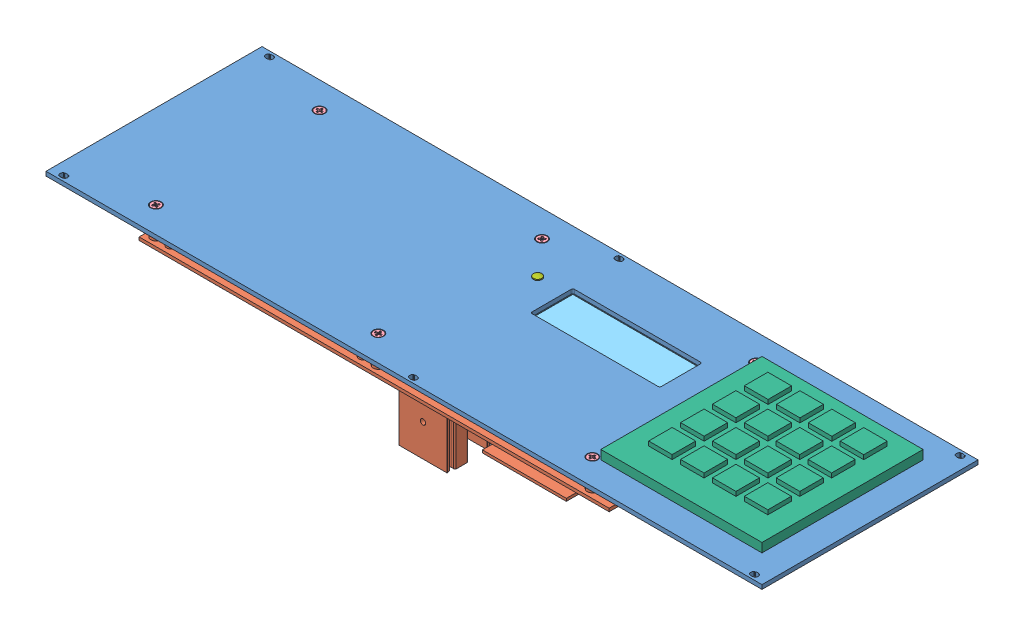
SolidWorks assembly MLA-0387-M0, configuration Default. Lengths in mm.
Overall size (426.52 63.69 128.7).
20 component instances, 9 part files, 41 mates.
Components (placement in the parent):
- MLA-0387-M1-1: MLA-0387-M1 [Default] at (-7.6092 -164.7802 590.2232) size (426.52 2.5 128.7)
- MLA-0387-P0-PB1-2: MLA-0387-P0-PB1 [Default] at (40.1108 198.8099 361.2233) x (1 0 0) z (0 1 0) size (280 107.5 53.19)
- pan_head_phillip_M2x4-1: pan_head_phillip_M2x4 [Default] at (204.3608 203.4199 260.2232) x (1 0 0) z (0 0 1) size (4 9.78 4)
- pan_head_phillip_M2x4-2: pan_head_phillip_M2x4 [Default] at (297.3608 203.4199 260.2232) x (-1 0 0) z (0 0 -1) size (4 9.78 4)
- pan_head_phillip_M2x4-3: pan_head_phillip_M2x4 [Default] at (204.3609 203.4199 315.2232) x (1 0 0) z (0 0 1) size (4 9.78 4)
- pan_head_phillip_M2x4-4: pan_head_phillip_M2x4 [Default] at (297.3609 203.4199 315.2232) x (1 0 0) z (0 0 1) size (4 9.78 4)
- SCREW_ISO 7046-1: SCREW_ISO 7046 [VIJAK M 3x 10] at (45.1108 215.3198 258.7232) x (0 -1 0) z (0 0 1) size (10 5.6 5.6)
- SCREW_ISO 7046-2: SCREW_ISO 7046 [VIJAK M 3x 10] at (45.1108 215.3198 356.2232) x (0 -1 0) z (-0.86006 0 -0.510193) size (10 5.6 5.6)
- SCREW_ISO 7046-3: SCREW_ISO 7046 [VIJAK M 3x 10] at (177.6108 215.2333 356.2232) x (0 -1 0) z (0.989385 0 -0.145321) size (10 5.6 5.6)
- SCREW_ISO 7046-4: SCREW_ISO 7046 [VIJAK M 3x 10] at (177.6108 215.3198 258.7232) x (0 -1 0) z (0.648115 0 0.761542) size (10 5.6 5.6)
- SCREW_ISO 7046-5: SCREW_ISO 7046 [VIJAK M 3x 10] at (305.1108 215.3198 258.7232) x (0 -1 0) z (0 0 1) size (10 5.6 5.6)
- SCREW_ISO 7046-6: SCREW_ISO 7046 [VIJAK M 3x 10] at (305.1108 215.3198 356.2232) x (0 -1 0) z (0 0 1) size (10 5.6 5.6)
- NHD-0420D3Z-FL-GBW-V3-3: NHD-0420D3Z-FL-GBW-V3 [Default] at (201.8609 201.8199 317.7232) x (1 0 0) z (0 1 0) size (98 60 10.6)
- Storm_7016010-4: Storm_7016010 [Default] at (309.2008 215.3198 355.2732) x (1 0 0) z (0 1 0) size (96 96 22)
- PLW5-500-1: PLW5-500 [Default] at (196.1108 215.3198 279.8132) size (5.25 13.97 5.07)
- MLA-0387-M7-1: MLA-0387-M7 [Default] at (49.1107 206.8199 361.2233) x (1 0 0) z (0 0 1) size (124.5 3 107.5)
- M2_5x8_Pan_head-1: M2_5x8_Pan_head [Default] at (54.1107 209.8199 258.7233) x (0 -1 0) z (-0.996671 0 -0.081529) size (13.3 7.99 5.14)
- M2_5x8_Pan_head-2: M2_5x8_Pan_head [Default] at (54.1107 209.8199 356.2233) x (0 -1 0) z (0.171735 0 0.985143) size (13.3 7.99 5.14)
- M2_5x8_Pan_head-3: M2_5x8_Pan_head [Default] at (168.6107 209.8199 356.2233) x (0 -1 0) z (0.996977 0 0.077698) size (13.3 7.99 5.14)
- M2_5x8_Pan_head-4: M2_5x8_Pan_head [Default] at (168.6107 209.8199 258.7233) x (0 -1 0) z (-0.397383 0 0.917653) size (13.3 7.99 5.14)
Mates (geometry in assembly coordinates):
- Concentric32: concentric aligned: cone of MLA-0387-M1-1 through (45.1108 215.3198 258.7232) axis (0 -1 0); cone of SCREW_ISO 7046-1 through (45.1108 213.8198 258.7232) axis (0 -1 0)
- Coincident46: coincident aligned: plane of MLA-0387-M1-1 through (0.4712 215.3198 287.1473) normal (0 1 0); plane of SCREW_ISO 7046-1 through (45.1108 215.3198 258.7232) normal (0 1 0)
- Concentric33: concentric aligned: cone of MLA-0387-M1-1 through (45.1108 215.3198 356.2232) axis (0 -1 0); cone of SCREW_ISO 7046-2 through (45.1108 213.8198 356.2232) axis (0 -1 0)
- Coincident47: coincident aligned: plane of MLA-0387-M1-1 through (0.4712 215.3198 287.1473) normal (0 1 0); plane of SCREW_ISO 7046-2 through (45.1108 215.3198 356.2232) normal (0 1 0)
- Coincident48: coincident: circle of MLA-0387-M1-1; cone of SCREW_ISO 7046-3 through (177.6108 213.7333 356.2232) axis (0 -1 0)
- Concentric34: concentric aligned: cone of MLA-0387-M1-1 through (177.6108 215.3198 258.7232) axis (0 -1 0); cone of SCREW_ISO 7046-4 through (177.6108 213.8198 258.7232) axis (0 -1 0)
- Coincident49: coincident aligned: plane of MLA-0387-M1-1 through (0.4712 215.3198 287.1473) normal (0 1 0); plane of SCREW_ISO 7046-4 through (177.6108 215.3198 258.7232) normal (0 1 0)
- Concentric35: concentric aligned: cone of MLA-0387-M1-1 through (305.1108 215.3198 258.7232) axis (0 -1 0); cone of SCREW_ISO 7046-5 through (305.1108 213.8198 258.7232) axis (0 -1 0)
- Coincident50: coincident aligned: plane of MLA-0387-M1-1 through (0.4712 215.3198 287.1473) normal (0 1 0); plane of SCREW_ISO 7046-5 through (305.1108 215.3198 258.7232) normal (0 1 0)
- Concentric36: concentric aligned: cone of MLA-0387-M1-1 through (305.1108 215.3198 356.2232) axis (0 -1 0); cone of SCREW_ISO 7046-6 through (305.1108 213.8198 356.2232) axis (0 -1 0)
- Coincident51: coincident aligned: plane of MLA-0387-M1-1 through (0.4712 215.3198 287.1473) normal (0 1 0); plane of SCREW_ISO 7046-6 through (305.1108 215.3198 356.2232) normal (0 1 0)
- Coincident60: coincident aligned: plane of MLA-0387-M1-1 through (0.4712 212.8198 287.1473) normal (0 -1 0); circle of MLA-0387-P0-PB1-2
- Concentric37: concentric aligned: cylinder of MLA-0387-M1-1 through (177.6108 215.3198 258.7232) axis (0 -1 0) radius 1.75; cylinder of MLA-0387-P0-PB1-2 through (177.6108 206.4198 258.7232) axis (0 -1 0) radius 3
- Concentric38: concentric aligned: cylinder of MLA-0387-M1-1 through (305.1108 215.3198 356.2232) axis (0 -1 0) radius 1.75; cylinder of MLA-0387-P0-PB1-2 through (305.1108 206.4199 356.2232) axis (0 -1 0) radius 3
- Coincident54: coincident aligned: circle of MLA-0387-P0-PB1-2; plane of NHD-0420D3Z-FL-GBW-V3-3 through (201.8609 201.8199 317.7232) normal (0 -1 0)
- Concentric39: concentric aligned: cylinder of NHD-0420D3Z-FL-GBW-V3-3 through (204.3608 201.8199 260.2232) axis (0 1 0) radius 1.25; cylinder of MLA-0387-P0-PB1-2 through (204.3608 197.4199 260.2232) axis (0 1 0) radius 2.175
- Concentric40: concentric aligned: cylinder of MLA-0387-P0-PB1-2 through (297.3608 197.4199 260.2232) axis (0 1 0) radius 2.175; cylinder of NHD-0420D3Z-FL-GBW-V3-3 through (297.3608 201.8199 260.2232) axis (0 1 0) radius 1.25
- Concentric41: concentric anti-aligned: cylinder of pan_head_phillip_M2x4-1 through (204.3608 205.2049 260.2232) axis (0 -1 0) radius 2; cylinder of NHD-0420D3Z-FL-GBW-V3-3 through (204.3608 201.8199 260.2232) axis (0 1 0) radius 1.25
- Coincident55: coincident anti-aligned: plane of pan_head_phillip_M2x4-1 through (204.3608 203.4199 260.2232) normal (0 -1 0); plane of NHD-0420D3Z-FL-GBW-V3-3 through (201.8609 203.4199 317.7232) normal (0 1 0)
- Concentric42: concentric anti-aligned: cylinder of pan_head_phillip_M2x4-2 through (297.3608 205.2049 260.2232) axis (0 -1 0) radius 2; cylinder of NHD-0420D3Z-FL-GBW-V3-3 through (297.3608 201.8199 260.2232) axis (0 1 0) radius 1.25
- Coincident56: coincident anti-aligned: plane of pan_head_phillip_M2x4-2 through (297.3608 203.4199 260.2232) normal (0 -1 0); plane of NHD-0420D3Z-FL-GBW-V3-3 through (201.8609 203.4199 317.7232) normal (0 1 0)
- Concentric43: concentric anti-aligned: cylinder of pan_head_phillip_M2x4-4 through (297.3609 205.2049 315.2232) axis (0 -1 0) radius 2; cylinder of NHD-0420D3Z-FL-GBW-V3-3 through (297.3609 201.8199 315.2232) axis (0 1 0) radius 1.25
- Coincident57: coincident anti-aligned: plane of pan_head_phillip_M2x4-4 through (297.3609 203.4199 315.2232) normal (0 -1 0); plane of NHD-0420D3Z-FL-GBW-V3-3 through (201.8609 203.4199 317.7232) normal (0 1 0)
- Concentric44: concentric anti-aligned: cylinder of pan_head_phillip_M2x4-3 through (204.3609 205.2049 315.2232) axis (0 -1 0) radius 2; cylinder of NHD-0420D3Z-FL-GBW-V3-3 through (204.3609 201.8199 315.2232) axis (0 1 0) radius 1.25
- Coincident58: coincident anti-aligned: plane of pan_head_phillip_M2x4-3 through (204.3609 203.4199 315.2232) normal (0 -1 0); plane of NHD-0420D3Z-FL-GBW-V3-3 through (201.8609 203.4199 317.7232) normal (0 1 0)
- Concentric45: concentric anti-aligned: circle of MLA-0387-M1-1; cylinder of Storm_7016010-4 through (389.2008 201.3198 339.2732) axis (0 1 0) radius 1.5
- Concentric46: concentric anti-aligned: circle of MLA-0387-M1-1; cylinder of Storm_7016010-4 through (325.2008 201.3198 275.2732) axis (0 1 0) radius 1.5
- Coincident61: coincident anti-aligned: plane of MLA-0387-M1-1 through (0.4712 215.3198 287.1473) normal (0 1 0); plane of Storm_7016010-4 through (309.2008 215.3198 355.2732) normal (0 -1 0)
- Concentric47: concentric aligned: cylinder of MLA-0387-M1-1 through (196.1108 205.3198 279.8132) axis (0 1 0) radius 1.98; cylinder of PLW5-500-1 through (196.1108 203.8054 279.8132) axis (0 1 0) radius 1.9304
- Coincident62: coincident aligned: plane of MLA-0387-M1-1 through (0.4712 215.3198 287.1473) normal (0 1 0); circle of PLW5-500-1
- Concentric48: concentric: circle of MLA-0387-P0-PB1-2; cylinder of MLA-0387-M7-1 through (54.1107 206.8199 258.7233) axis (0 1 0) radius 1.5
- Concentric49: concentric: cylinder of MLA-0387-P0-PB1-2 through (168.6107 194.9717 356.2233) axis (0 -1 0) radius 1.0065; cylinder of MLA-0387-M7-1 through (168.6107 206.8199 356.2233) axis (0 1 0) radius 1.5
- Coincident63: coincident anti-aligned: plane of MLA-0387-P0-PB1-2 through (171.1607 206.8199 356.2233) normal (0 1 0); plane of MLA-0387-M7-1 through (49.1107 206.8199 361.2233) normal (0 -1 0)
- Concentric50: concentric: cylinder of MLA-0387-P0-PB1-2 through (54.1107 194.9716 258.7233) axis (0 -1 0) radius 1.0065; cylinder of M2_5x8_Pan_head-1 through (54.1107 204.379 258.7233) axis (0 1 0) radius 1
- Coincident64: coincident anti-aligned: plane of MLA-0387-M7-1 through (49.1107 209.8199 361.2233) normal (0 1 0); plane of M2_5x8_Pan_head-1 through (55.8982 209.8199 258.8696) normal (0 -1 0)
- Concentric51: concentric: cylinder of MLA-0387-P0-PB1-2 through (54.1107 194.9717 356.2233) axis (0 -1 0) radius 1.0065; cylinder of M2_5x8_Pan_head-2 through (54.1107 204.3791 356.2233) axis (0 1 0) radius 1
- Coincident65: coincident anti-aligned: plane of MLA-0387-M7-1 through (49.1107 209.8199 361.2233) normal (0 1 0); plane of M2_5x8_Pan_head-2 through (53.8027 209.8199 354.4565) normal (0 -1 0)
- Concentric52: concentric: cylinder of MLA-0387-P0-PB1-2 through (168.6107 194.9717 356.2233) axis (0 -1 0) radius 1.0065; cylinder of M2_5x8_Pan_head-3 through (168.6107 204.3791 356.2233) axis (0 1 0) radius 1
- Coincident66: coincident anti-aligned: plane of MLA-0387-M7-1 through (49.1107 209.8199 361.2233) normal (0 1 0); plane of M2_5x8_Pan_head-3 through (166.8226 209.8199 356.084) normal (0 -1 0)
- Concentric53: concentric: cylinder of MLA-0387-P0-PB1-2 through (168.6107 194.9716 258.7233) axis (0 -1 0) radius 1.0065; cylinder of M2_5x8_Pan_head-4 through (168.6107 204.379 258.7233) axis (0 1 0) radius 1
- Coincident67: coincident anti-aligned: plane of MLA-0387-M7-1 through (49.1107 209.8199 361.2233) normal (0 1 0); plane of M2_5x8_Pan_head-4 through (169.3234 209.8199 257.0775) normal (0 -1 0)
